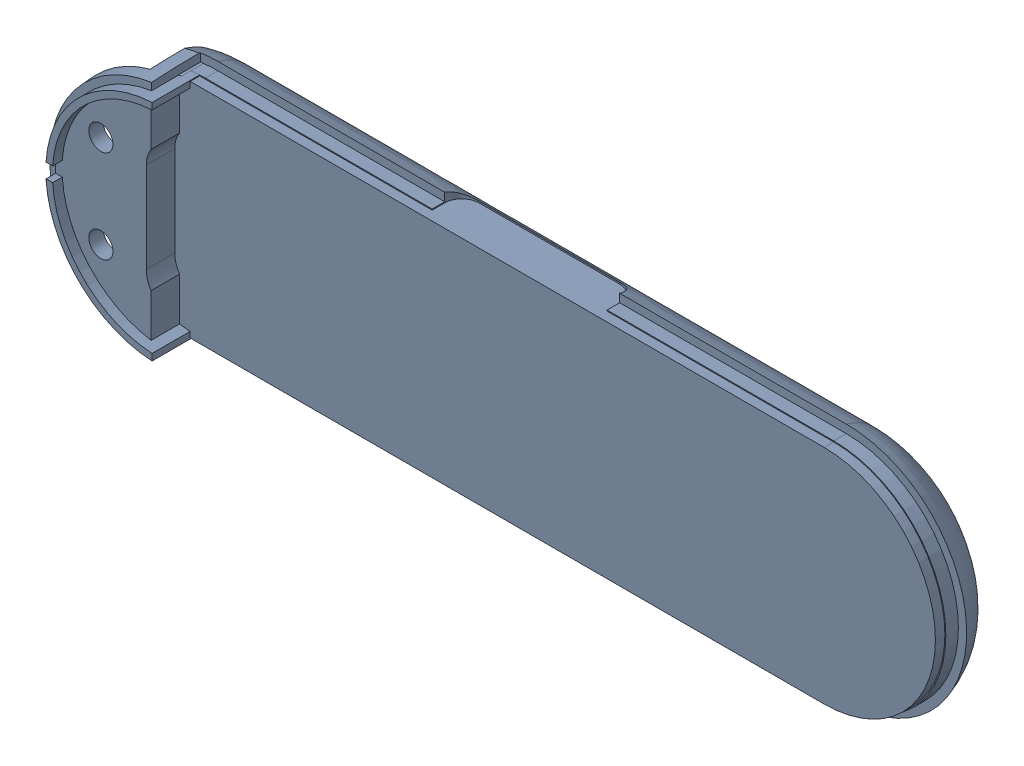
SolidWorks assembly REAR_COVER_SUBASSY_AWG_W_RGB_AS_ASM, configuration Default. Lengths in mm.
Overall size (90.48 26.3 10.45).
3 component instances, 2 part files, 0 mates.
Components (placement in the parent):
- REAR_COVER_ALUMINUM_AWG_RGB_121-1: REAR_COVER_ALUMINUM_AWG_RGB_121 [Default] at origin size (90.48 26.3 10.45)
- MAGNET_9-1: MAGNET_9 [Default] at (7.25 9.3 -20.82) x (-1 0 0) z (0 1 0) size (1.6 1.6 1.6)
- MAGNET_9-2: MAGNET_9 [Default] at (-7.25 9.3 -20.82) x (-1 0 0) z (0 1 0) size (1.6 1.6 1.6)
